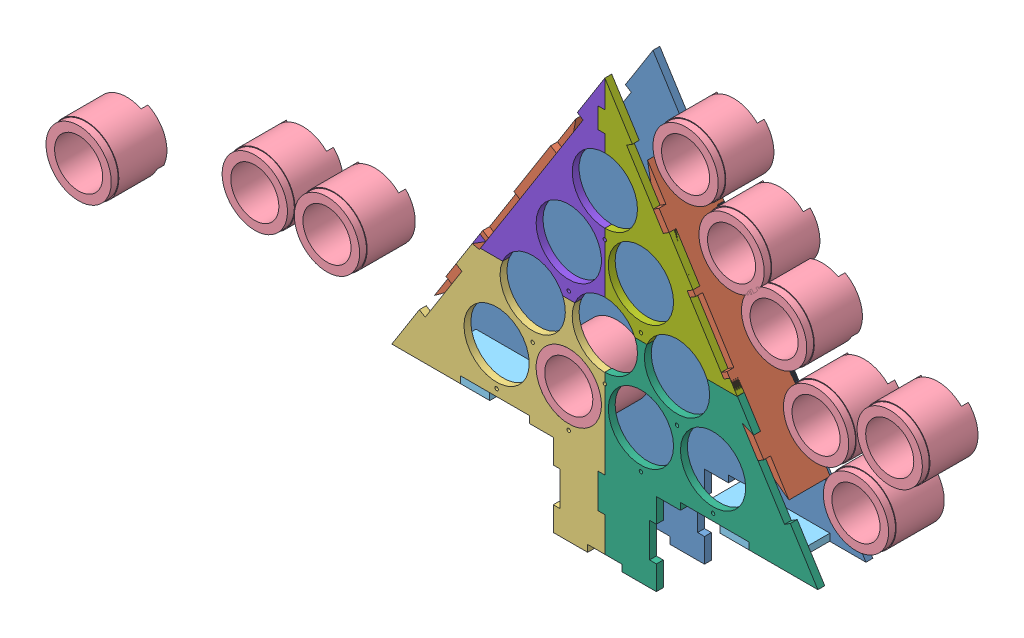
SolidWorks assembly Assemblage1, configuration Défaut. Lengths in mm.
Overall size (1290.71 610.2 80).
19 component instances, 8 part files, 35 mates.
Components (placement in the parent):
- bot-1: bot [Défaut] at (-67.0522 -214.8309 620) size (620 610.2 10)
- cote-1: cote [Défaut] at (-213.6004 24.9263 660) x (0.534483 0.845179 0) z (-0.845179 0.534483 0) size (385 80 10)
- cote-2: cote [Défaut] at (79.496 24.9263 660) x (0.534483 -0.845179 0) z (0.845179 0.534483 0) size (385 80 10)
- top_bas-1: top_bas [Défaut] at (-67.0522 -139.188 690) size (310 305.1 10)
- cercle verre-1: cercle verre [Défaut] at (-832.7652 -214.8227 630) x (0.942008 0.33559 0) z (0 0 1) size (97 96 80)
- cercle verre-2: cercle verre [Défaut] at (-576.4025 -123.7505 630) size (97 96 80)
- cercle verre-3: cercle verre [Défaut] at (-471.4025 -123.7505 630) size (97 96 80)
- cercle verre-4: cercle verre [Défaut] at (-119.5522 -139.188 630) x (0.135913 -0.990721 0) z (0 0 1) size (97 96 80)
- cercle verre-5: cercle verre [Défaut] at (240.3197 -8.5957 630) size (97 96 80)
- cercle verre-6: cercle verre [Défaut] at (179.2589 82.1749 630) x (0.959277 0.282468 0) z (0 0 1) size (97 96 80)
- cercle verre-7: cercle verre [Défaut] at (117.3543 146.9759 630) size (97 96 80)
- cercle verre-8: cercle verre [Défaut] at (50.4354 225.136 630) size (97 96 80)
- cercle verre-9: cercle verre [Défaut] at (347.4839 16.7546 630) size (97 96 80)
- cercle verre-10: cercle verre [Défaut] at (298.3674 -90.0445 630) size (97 96 80)
- arriere-2: arriere [Défaut] at (-259.5522 -214.8309 660) x (1 0 0) z (0 1 0) size (130 80 10)
- arriere-3: arriere [Défaut] at (125.4478 -214.4017 660) x (-1 0 0) z (0 1 0) size (130 80 10)
- top_bas_droit-2: top_bas_droit [Défaut] at (-67.0522 -138.7588 690) size (320 305.1 10)
- top_haut_droit-1: top_haut_droit [Défaut] at (-67.0522 -139.188 690) size (202.94 305.1 10)
- top_haut_gauche-1: top_haut_gauche [Défaut] at (-67.0522 -139.188 690) size (192.94 305.1 10)
Mates (geometry in assembly coordinates):
- Coïncidente1: coincident anti-aligned: plane of bot-1 through (-152.1349 122.1219 620) normal (-0.845179 0.534483 0); plane of cote-1 through (-213.6004 24.9263 660) normal (0.845179 -0.534483 0)
- Coïncidente2: coincident anti-aligned: plane of bot-1 through (-67.0522 -214.8309 630) normal (0 0 1); plane of cote-1 through (-67.0522 275.3732 630) normal (0 0 -1)
- Coïncidente3: coincident anti-aligned: plane of bot-1 through (-160.5867 127.4668 620) normal (0.534483 0.845179 0); plane of cote-1 through (-152.1349 122.1219 630) normal (-0.534483 -0.845179 0)
- Coïncidente4: coincident anti-aligned: plane of bot-1 through (18.0305 122.1219 620) normal (0.845179 0.534483 0); plane of cote-2 through (79.496 24.9263 660) normal (-0.845179 -0.534483 0)
- Coïncidente5: coincident anti-aligned: plane of bot-1 through (-67.0522 -214.8309 630) normal (0 0 1); plane of cote-2 through (242.9478 -214.8309 630) normal (0 0 -1)
- Coïncidente6: coincident anti-aligned: plane of bot-1 through (26.4823 127.4668 620) normal (-0.534483 0.845179 0); plane of cote-2 through (18.0305 122.1219 630) normal (0.534483 -0.845179 0)
- Coïncidente10: coincident anti-aligned: plane of cote-2 through (242.9478 -214.8309 690) normal (0 0 1); plane of top-1 through (-67.0522 -139.188 690) normal (0 0 -1)
- Coïncidente14: coincident aligned: plane of cercle verre-10 through (298.3674 -90.0445 700) normal (0 0 1); plane of cercle verre-9 through (347.4839 16.7546 700) normal (0 0 1)
- Coïncidente15: coincident aligned: plane of cercle verre-10 through (298.3674 -90.0445 700) normal (0 0 1); plane of cercle verre-3 through (-471.4025 -123.7505 700) normal (0 0 1)
- Coïncidente16: coincident aligned: plane of cercle verre-10 through (298.3674 -90.0445 700) normal (0 0 1); plane of cercle verre-8 through (50.4354 225.136 700) normal (0 0 1)
- Coïncidente17: coincident aligned: plane of cercle verre-10 through (298.3674 -90.0445 700) normal (0 0 1); plane of cercle verre-4 through (-119.5522 -139.188 700) normal (0 0 1)
- Coïncidente18: coincident aligned: plane of cercle verre-10 through (298.3674 -90.0445 700) normal (0 0 1); plane of cercle verre-2 through (-576.4025 -123.7505 700) normal (0 0 1)
- Coïncidente19: coincident aligned: plane of cercle verre-10 through (298.3674 -90.0445 700) normal (0 0 1); plane of cercle verre-5 through (240.3197 -8.5957 700) normal (0 0 1)
- Coïncidente20: coincident aligned: plane of cercle verre-10 through (298.3674 -90.0445 700) normal (0 0 1); plane of cercle verre-7 through (117.3543 146.9759 700) normal (0 0 1)
- Coïncidente21: coincident aligned: plane of cercle verre-10 through (298.3674 -90.0445 700) normal (0 0 1); plane of cercle verre-6 through (179.2589 82.1749 700) normal (0 0 1)
- Coïncidente22: coincident aligned: plane of cercle verre-10 through (298.3674 -90.0445 700) normal (0 0 1); plane of top-1 through (-67.0522 -139.188 700) normal (0 0 1)
- Coïncidente30: coincident aligned: plane of bot-1 through (-67.0522 -214.8309 620) normal (0 0 -1); plane of arriere-2 through (-277.0522 -204.8309 620) normal (0 0 -1)
- Coïncidente31: coincident aligned: plane of bot-1 through (-377.0522 -214.8309 630) normal (0 -1 0); plane of arriere-2 through (-259.5522 -214.8309 660) normal (0 -1 0)
- Coïncidente32: coincident anti-aligned: plane of bot-1 through (-177.0522 -214.8309 620) normal (-1 0 0); plane of arriere-2 through (-177.0522 -204.8309 630) normal (1 0 0)
- Coïncidente33: coincident aligned: plane of cote-1 through (-222.0522 30.2711 660) normal (-0.845179 0.534483 0); plane of top_bas-1 through (-377.0522 -214.8309 700) normal (-0.845179 0.534483 0)
- Coïncidente34: coincident anti-aligned: plane of cote-1 through (-328.5142 -156.7873 690) normal (-0.534483 -0.845179 0); plane of top_bas-1 through (-336.966 -151.4424 690) normal (0.534483 0.845179 0)
- Coïncidente37: coincident aligned: plane of top_bas-1 through (-67.0522 -139.188 700) normal (0 0 1); plane of top_bas_droit-2 through (-67.0522 -138.7588 700) normal (0 0 1)
- Coïncidente38: coincident anti-aligned: plane of top_bas-1 through (-67.0522 275.3732 690) normal (1 0 0); plane of top_bas_droit-2 through (-67.0522 -356.1057 690) normal (-1 0 0)
- Coïncidente39: coincident aligned: plane of top_bas-1 through (-92.0522 -324.8309 690) normal (0 -1 0); plane of top_bas_droit-2 through (-92.0522 -324.8309 690) normal (0 -1 0)
- Coïncidente40: coincident anti-aligned: plane of arriere-3 through (125.4478 -204.4017 660) normal (0 1 0); plane of top_bas_droit-2 through (142.9478 -204.4017 690) normal (0 -1 0)
- Coïncidente41: coincident aligned: plane of arriere-3 through (142.9478 -204.4017 700) normal (0 0 1); plane of top_bas_droit-2 through (-67.0522 -138.7588 700) normal (0 0 1)
- Coïncidente42: coincident anti-aligned: plane of arriere-3 through (42.9478 -204.4017 690) normal (-1 0 0); plane of top_bas_droit-2 through (42.9478 -214.4017 690) normal (1 0 0)
- Coïncidente43: coincident anti-aligned: plane of cote-2 through (242.9478 -214.8309 690) normal (0 0 1); plane of top_haut_droit-1 through (-67.0522 -139.188 690) normal (0 0 -1)
- Coïncidente44: coincident aligned: plane of cote-2 through (87.9478 30.2711 660) normal (0.845179 0.534483 0); plane of top_haut_droit-1 through (-67.0522 275.3732 700) normal (0.845179 0.534483 0)
- Coïncidente45: coincident anti-aligned: plane of cote-2 through (-35.4178 206.6399 690) normal (-0.534483 0.845179 0); plane of top_haut_droit-1 through (-35.4178 206.6399 690) normal (0.534483 -0.845179 0)
- Coïncidente46: coincident anti-aligned: plane of top_haut_droit-1 through (-67.0522 275.3732 690) normal (-1 0 0); plane of top_haut_gauche-1 through (-67.0522 275.3732 690) normal (1 0 0)
- Coïncidente47: coincident aligned: plane of top_haut_droit-1 through (-67.0522 -139.188 700) normal (0 0 1); plane of top_haut_gauche-1 through (-67.0522 -139.188 700) normal (0 0 1)
- Coïncidente48: coincident anti-aligned: plane of top_haut_droit-1 through (-67.0522 235.3732 690) normal (0 1 0); plane of top_haut_gauche-1 through (-67.0522 235.3732 690) normal (0 -1 0)
- Coïncidente49: coincident aligned: plane of top_bas-1 through (-67.0522 -139.188 700) normal (0 0 1); plane of cercle verre-4 through (-119.5522 -139.188 700) normal (0 0 1)
- Coaxiale1: concentric anti-aligned: cylinder of top_bas-1 through (-119.5522 -139.188 700) axis (0 0 -1) radius 47.5; cylinder of cercle verre-4 through (-119.5522 -139.188 690) axis (0 0 1) radius 47.5
